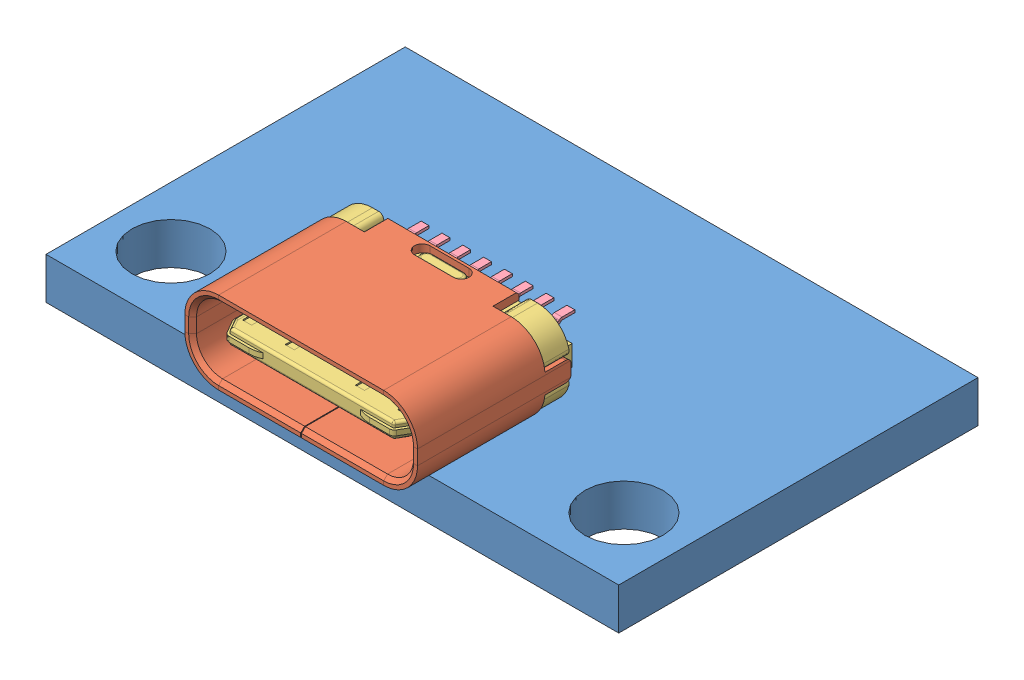
SolidWorks assembly 装配体1, configuration 默认. Lengths in mm.
Overall size (22 4.76 15).
20 component instances, 4 part files, 3 mates.
Components (placement in the parent):
- type_c_motherboard-1: type_c_motherboard [默认] at (-70.9859 7.4452 0) size (22 1.6 13.8)
- USB Type C Socket^PCB_Riden TC64 Module 01a(2)_Riden TC64 Module 01a-1: USB Type C Socket^PCB_Riden TC64 Module 01a(2)_Riden TC64 Module 01a [默认] at (-70.9859 10.6252 5.15) size (8.95 3.16 7.36)
  - USB_C_SHELL^USB Type C Socket_PCB_Riden TC64 Module 01a(2)_Riden TC64 Module 01a-1: USB_C_SHELL^USB Type C Socket_PCB_Riden TC64 Module 01a(2)_Riden TC64 Module 01a [默认] at origin size (8.95 3.16 5.9) (virtual)
  - USB_C_Body^USB Type C Socket_PCB_Riden TC64 Module 01a(2)_Riden TC64 Module 01a-1: USB_C_Body^USB Type C Socket_PCB_Riden TC64 Module 01a(2)_Riden TC64 Module 01a [默认] at (0 0 -1.21) size (8.77 3.06 6.05) (virtual)
  - USB_C_PIN^USB Type C Socket_PCB_Riden TC64 Module 01a(2)_Riden TC64 Module 01a-1: USB_C_PIN^USB Type C Socket_PCB_Riden TC64 Module 01a(2)_Riden TC64 Module 01a [默认] at (3 0.5 -3.47) x (-1 0 0) z (0 -1 0) size (0.3 1.94 0.21) (virtual)
  - USB_C_PIN^USB Type C Socket_PCB_Riden TC64 Module 01a(2)_Riden TC64 Module 01a-2: USB_C_PIN^USB Type C Socket_PCB_Riden TC64 Module 01a(2)_Riden TC64 Module 01a [默认] at (2.2 0.5 -3.47) x (-1 0 0) z (0 -1 0) size (0.3 1.94 0.21) (virtual)
  - USB_C_PIN^USB Type C Socket_PCB_Riden TC64 Module 01a(2)_Riden TC64 Module 01a-3: USB_C_PIN^USB Type C Socket_PCB_Riden TC64 Module 01a(2)_Riden TC64 Module 01a [默认] at (1.4 0.5 -3.47) x (-1 0 0) z (0 -1 0) size (0.3 1.94 0.21) (virtual)
  - USB_C_PIN^USB Type C Socket_PCB_Riden TC64 Module 01a(2)_Riden TC64 Module 01a-4: USB_C_PIN^USB Type C Socket_PCB_Riden TC64 Module 01a(2)_Riden TC64 Module 01a [默认] at (0.6 0.5 -3.47) x (-1 0 0) z (0 -1 0) size (0.3 1.94 0.21) (virtual)
  - USB_C_PIN^USB Type C Socket_PCB_Riden TC64 Module 01a(2)_Riden TC64 Module 01a-5: USB_C_PIN^USB Type C Socket_PCB_Riden TC64 Module 01a(2)_Riden TC64 Module 01a [默认] at (-0.2 0.5 -3.47) x (-1 0 0) z (0 -1 0) size (0.3 1.94 0.21) (virtual)
  - USB_C_PIN^USB Type C Socket_PCB_Riden TC64 Module 01a(2)_Riden TC64 Module 01a-6: USB_C_PIN^USB Type C Socket_PCB_Riden TC64 Module 01a(2)_Riden TC64 Module 01a [默认] at (-2.6 0.5 -3.47) x (-1 0 0) z (0 -1 0) size (0.3 1.94 0.21) (virtual)
  - USB_C_PIN^USB Type C Socket_PCB_Riden TC64 Module 01a(2)_Riden TC64 Module 01a-7: USB_C_PIN^USB Type C Socket_PCB_Riden TC64 Module 01a(2)_Riden TC64 Module 01a [默认] at (-1.8 0.5 -3.47) x (-1 0 0) z (0 -1 0) size (0.3 1.94 0.21) (virtual)
  - USB_C_PIN^USB Type C Socket_PCB_Riden TC64 Module 01a(2)_Riden TC64 Module 01a-8: USB_C_PIN^USB Type C Socket_PCB_Riden TC64 Module 01a(2)_Riden TC64 Module 01a [默认] at (-3 -0.45 -3.45) x (1 0 0) z (0 1 0) size (0.3 1.94 0.21) (virtual)
  - USB_C_PIN^USB Type C Socket_PCB_Riden TC64 Module 01a(2)_Riden TC64 Module 01a-9: USB_C_PIN^USB Type C Socket_PCB_Riden TC64 Module 01a(2)_Riden TC64 Module 01a [默认] at (-2.2 -0.45 -3.45) x (1 0 0) z (0 1 0) size (0.3 1.94 0.21) (virtual)
  - USB_C_PIN^USB Type C Socket_PCB_Riden TC64 Module 01a(2)_Riden TC64 Module 01a-10: USB_C_PIN^USB Type C Socket_PCB_Riden TC64 Module 01a(2)_Riden TC64 Module 01a [默认] at (-1.4 -0.45 -3.45) x (1 0 0) z (0 1 0) size (0.3 1.94 0.21) (virtual)
  - USB_C_PIN^USB Type C Socket_PCB_Riden TC64 Module 01a(2)_Riden TC64 Module 01a-11: USB_C_PIN^USB Type C Socket_PCB_Riden TC64 Module 01a(2)_Riden TC64 Module 01a [默认] at (-0.6 -0.45 -3.45) x (1 0 0) z (0 1 0) size (0.3 1.94 0.21) (virtual)
  - USB_C_PIN^USB Type C Socket_PCB_Riden TC64 Module 01a(2)_Riden TC64 Module 01a-12: USB_C_PIN^USB Type C Socket_PCB_Riden TC64 Module 01a(2)_Riden TC64 Module 01a [默认] at (1 -0.45 -3.45) x (1 0 0) z (0 1 0) size (0.3 1.94 0.21) (virtual)
  - USB_C_PIN^USB Type C Socket_PCB_Riden TC64 Module 01a(2)_Riden TC64 Module 01a-13: USB_C_PIN^USB Type C Socket_PCB_Riden TC64 Module 01a(2)_Riden TC64 Module 01a [默认] at (0.2 -0.45 -3.45) x (1 0 0) z (0 1 0) size (0.3 1.94 0.21) (virtual)
  - USB_C_PIN^USB Type C Socket_PCB_Riden TC64 Module 01a(2)_Riden TC64 Module 01a-14: USB_C_PIN^USB Type C Socket_PCB_Riden TC64 Module 01a(2)_Riden TC64 Module 01a [默认] at (1.8 -0.45 -3.45) x (1 0 0) z (0 1 0) size (0.3 1.94 0.21) (virtual)
  - USB_C_PIN^USB Type C Socket_PCB_Riden TC64 Module 01a(2)_Riden TC64 Module 01a-15: USB_C_PIN^USB Type C Socket_PCB_Riden TC64 Module 01a(2)_Riden TC64 Module 01a [默认] at (2.6 -0.45 -3.45) x (1 0 0) z (0 1 0) size (0.3 1.94 0.21) (virtual)
  - USB_C_PIN^USB Type C Socket_PCB_Riden TC64 Module 01a(2)_Riden TC64 Module 01a-16: USB_C_PIN^USB Type C Socket_PCB_Riden TC64 Module 01a(2)_Riden TC64 Module 01a [默认] at (-1 0.5 -3.47) x (-1 0 0) z (0 -1 0) size (0.3 1.94 0.21) (virtual)
Mates (geometry in assembly coordinates):
- 重合1: coincident: plane of type_c_motherboard-1 through (-70.9859 9.0452 0) normal (0 1 0); plane of USB Type C Socket^PCB_Riden TC64 Module 01a(2)_Riden TC64 Module 01a-1/USB_C_SHELL^USB Type C Socket_PCB_Riden TC64 Module 01a(2)_Riden TC64 Module 01a-1 through (-74.1559 9.0452 9.913) normal (0 -1 0)
- 距离1: distance = 6.53 mm: plane of type_c_motherboard-1 through (-81.9859 9.0452 6.9) normal (-1 0 0); plane of USB Type C Socket^PCB_Riden TC64 Module 01a(2)_Riden TC64 Module 01a-1/USB_C_SHELL^USB Type C Socket_PCB_Riden TC64 Module 01a(2)_Riden TC64 Module 01a-1 through (-75.4559 10.9052 8.1) normal (-1 0 0)
- 距离2: distance = 1.2 mm aligned: plane of USB Type C Socket^PCB_Riden TC64 Module 01a(2)_Riden TC64 Module 01a-1/USB_C_SHELL^USB Type C Socket_PCB_Riden TC64 Module 01a(2)_Riden TC64 Module 01a-1 through (-75.4559 10.3452 8.1) normal (0 0 1); plane of type_c_motherboard-1 through (-81.9859 9.0452 6.9) normal (0 0 1)
